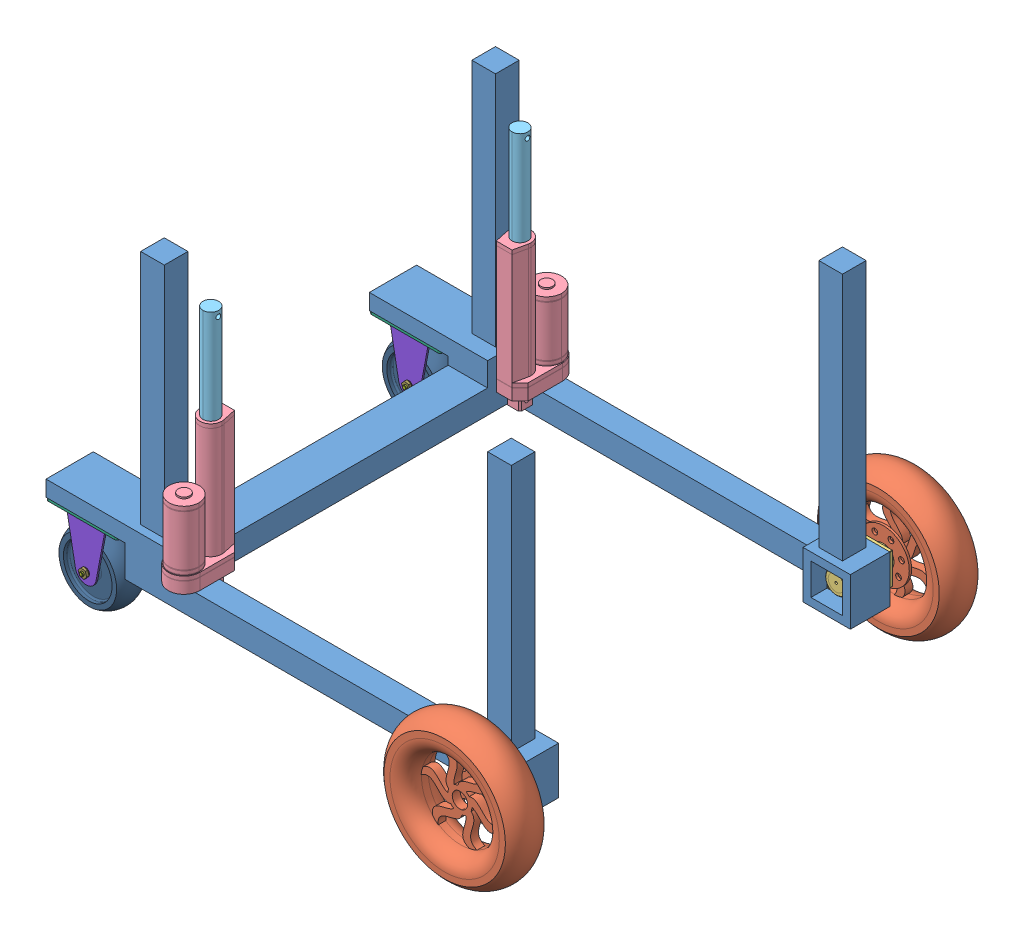
SolidWorks assembly Automatic Wheel Chair, configuration Default. Lengths in mm.
Overall size (717.52 470.88 599).
25 component instances, 12 part files, 35 mates.
Components (placement in the parent):
- Part1^Automatic Wheel Chair-1: Part1^Automatic Wheel Chair [Default] x (1 0 0) z (0 1 0) size (600 470 375) (virtual)
- motorbike wheel-1: motorbike wheel [Default] at (228.5832 -15.7536 275.1) x (0 0 1) z (0.96319 0.268823 0) size (48.77 178.47 178.47)
- motorbike wheel-2: motorbike wheel [Default] at (195.8761 -5.9162 -275.1) x (0 0 -1) z (-0.655088 0.755552 0) size (48.77 178.47 178.47)
- LINOS-FI-1030-35C_bulk-1: LINOS-FI-1030-35C_bulk [Default] at (220 15 227) x (0 0 1) z (-1 0 0) size (60.2 40 40)
- LINOS-FI-1030-35C_bulk-2: LINOS-FI-1030-35C_bulk [Default] at (220 15 -227) x (0 0 -1) z (1 0 0) size (60.2 40 40)
- 100mm Body.step-3: 100mm Body.step [Default] at (-180 30 -203) x (0 0 1) z (1 0 0) size (74 184 40)
- 100mm Rod.step-2: 100mm Rod.step [Default] at (-180 315.7736 -196) x (1 0 0) z (0 0 -1) size (20.01 121 20)
- 100mm Body.step-2: 100mm Body.step [Default] at (-180 30 203) x (0 0 -1) z (-1 0 0) size (74 184 40)
- 100mm Rod.step-1: 100mm Rod.step [Default] at (-180 315.7736 196) x (-1 0 0) z (0 0 1) size (20.01 121 20)
- Castor Wheel Assembly-3: Castor Wheel Assembly [Default] at (-334.542 8.6584 218.6333) x (0 0 -1) z (1 0 0) size (60 128.96 125.41)
  - Top-1: Top [Default] at (13.6333 28.3416 29.542) size (60 15.5 90)
  - Holder-1: Holder [Default] at (37.7896 -35.6584 26.7167) x (-0.998933 0 -0.046183) z (0.04107 -0.457338 -0.888344) size (50 12 12)
  - HOLDER 2-1: HOLDER 2 [Default] at (-5.2161 -32.9337 4.1925) x (-0.998933 0 -0.046183) z (0.046183 0 -0.998933) size (40 78 51.06)
  - bottom-1: bottom [Default] at (13.6333 18.3416 29.542) x (0.999827 0 0.018618) z (-0.018618 0 0.999827) size (27 8 25.19)
  - Wheel-1: Wheel [Default] at (0.3296 -35.6584 24.9849) x (0.998933 0 0.046183) z (0.035525 -0.638971 -0.76841) size (35 88 88)
  - washer-1: washer [Default] at (-6.6629 -35.6584 24.6616) x (0.998933 0 0.046183) z (-0.044089 0.297668 0.953651) size (0.5 10 10)
  - Nut-1: Nut [Default] at (-10.1592 -35.6584 24.4999) x (0.998933 0 0.046183) z (-0.03002 0.759916 0.649328) size (3 10 11.55)
- Castor Wheel Assembly-4: Castor Wheel Assembly [Default] at (-334.542 8.6584 -191.3667) x (0 0 -1) z (1 0 0) size (60 128.96 125.41)
  - Top-1: Top [Default] at (13.6333 28.3416 29.542) size (60 15.5 90)
  - Holder-1: Holder [Default] at (37.7896 -35.6584 26.7167) x (-0.998933 0 -0.046183) z (0.04107 -0.457338 -0.888344) size (50 12 12)
  - HOLDER 2-1: HOLDER 2 [Default] at (-5.2161 -32.9337 4.1925) x (-0.998933 0 -0.046183) z (0.046183 0 -0.998933) size (40 78 51.06)
  - bottom-1: bottom [Default] at (13.6333 18.3416 29.542) x (0.999827 0 0.018618) z (-0.018618 0 0.999827) size (27 8 25.19)
  - Wheel-1: Wheel [Default] at (0.3296 -35.6584 24.9849) x (0.998933 0 0.046183) z (0.035525 -0.638971 -0.76841) size (35 88 88)
  - washer-1: washer [Default] at (-6.6629 -35.6584 24.6616) x (0.998933 0 0.046183) z (-0.044089 0.297668 0.953651) size (0.5 10 10)
  - Nut-1: Nut [Default] at (-10.1592 -35.6584 24.4999) x (0.998933 0 0.046183) z (-0.03002 0.759916 0.649328) size (3 10 11.55)
Mates (geometry in assembly coordinates):
- InPlace1: in place: plane of Part1^Automatic Wheel Chair-1 through (0 0 0) normal (0 1 0); moOrthogonalPlaneRef_w of Part1^Automatic Wheel Chair-1 through (0 0 0) normal (0 0 -1); plane of Part1^Automatic Wheel Chair-1 through (0 0 0) normal (1 0 0); unknown of Part1^Automatic Wheel Chair-1
- Coincident1: coincident aligned: 
- Coincident2: coincident aligned: plane of Part1^Automatic Wheel Chair-1 through (0 0 0) normal (0 0 -1)
- Coincident3: coincident anti-aligned: plane of Part1^Automatic Wheel Chair-1 through (0 0 0) normal (1 0 0)
- Parallel3: parallel anti-aligned: plane of Part1^Automatic Wheel Chair-1 through (0 30 235) normal (0 0 1); plane of motorbike wheel-1 through (220 15 257.1) normal (0 0 -1)
- Parallel4: parallel anti-aligned: plane of Part1^Automatic Wheel Chair-1 through (0 30 -235) normal (0 0 -1); plane of motorbike wheel-2 through (220 15 -257.1) normal (0 0 1)
- Concentric19: concentric anti-aligned: cylinder of motorbike wheel-1 through (220 15 260.1) axis (0 0 1) radius 9.7956; cylinder of LINOS-FI-1030-35C_bulk-1 through (220 15 257) axis (0 0 -1) radius 14.25
- Concentric20: concentric anti-aligned: cylinder of motorbike wheel-2 through (220 15 -247.1) axis (0 0 -1) radius 9.7956; cylinder of LINOS-FI-1030-35C_bulk-2 through (220 15 -257) axis (0 0 1) radius 14.25
- Coincident36: coincident anti-aligned: plane of Part1^Automatic Wheel Chair-1 through (200 35 -235) normal (0 -1 0); plane of LINOS-FI-1030-35C_bulk-2 through (240 35 -249) normal (0 1 0)
- Coincident37: coincident anti-aligned: plane of Part1^Automatic Wheel Chair-1 through (200 35 -235) normal (0 -1 0); plane of LINOS-FI-1030-35C_bulk-1 through (200 35 249) normal (0 1 0)
- Coincident38: coincident anti-aligned: plane of Part1^Automatic Wheel Chair-1 through (200 -5 -235) normal (1 0 0); plane of LINOS-FI-1030-35C_bulk-1 through (200 15 227) normal (-1 0 0)
- Coincident39: coincident anti-aligned: plane of Part1^Automatic Wheel Chair-1 through (240 -5 -235) normal (-1 0 0); plane of LINOS-FI-1030-35C_bulk-2 through (240 15 -227) normal (1 0 0)
- Coincident40: coincident aligned: plane of Part1^Automatic Wheel Chair-1 through (0 30 -205) normal (0 0 1); plane of LINOS-FI-1030-35C_bulk-2 through (240 -5 -205) normal (0 0 1)
- Coincident41: coincident aligned: plane of Part1^Automatic Wheel Chair-1 through (0 30 205) normal (0 0 -1); plane of LINOS-FI-1030-35C_bulk-1 through (200 -5 205) normal (0 0 -1)
- Coincident42: coincident anti-aligned: plane of motorbike wheel-1 through (220 15 257.1) normal (0 0 -1); plane of LINOS-FI-1030-35C_bulk-1 through (220 15 257.1) normal (0 0 1)
- Coincident43: coincident anti-aligned: plane of motorbike wheel-2 through (220 15 -257.1) normal (0 0 1); plane of LINOS-FI-1030-35C_bulk-2 through (220 15 -257.1) normal (0 0 -1)
- Concentric21: concentric aligned: cylinder of 100mm Body.step-2 through (-180 21.7157 196) axis (0 1 0) radius 10; cylinder of 100mm Rod.step-1 through (-180 194.7736 196) axis (0 1 0) radius 10
- LimitDistance1: limit distance = 119.7736 mm aligned: plane of 100mm Rod.step-1 through (-180 315.7736 196) normal (0 1 0); plane of 100mm Body.step-2 through (-180 196 196) normal (0 1 0)
- Parallel1: parallel aligned: cylinder of 100mm Body.step-2 through (-162.5147 21 196) axis (-1 0 0) radius 3; cylinder of 100mm Rod.step-1 through (-169.999 308.7736 196) axis (-1 0 0) radius 3
- Coincident58: coincident anti-aligned: plane of Part1^Automatic Wheel Chair-1 through (0 30 0) normal (0 1 0); plane of 100mm Body.step-2 through (-180 30 230) normal (0 -1 0)
- Coincident59: coincident anti-aligned: plane of Part1^Automatic Wheel Chair-1 through (-200 30 0) normal (1 0 0); plane of 100mm Body.step-2 through (-200 50 230) normal (-1 0 0)
- Coincident60: coincident anti-aligned: plane of Part1^Automatic Wheel Chair-1 through (0 30 205) normal (0 0 -1); plane of 100mm Body.step-2 through (-173 12 205) normal (0 0 1)
- Concentric22: concentric aligned: cylinder of 100mm Body.step-3 through (-180 21.7157 -196) axis (0 1 0) radius 10; cylinder of 100mm Rod.step-2 through (-180 194.7736 -196) axis (0 1 0) radius 10
- LimitDistance2: limit distance = 119.7736 mm aligned: plane of 100mm Rod.step-2 through (-180 315.7736 -196) normal (0 1 0); plane of 100mm Body.step-3 through (-180 196 -196) normal (0 1 0)
- Parallel5: parallel aligned: cylinder of 100mm Body.step-3 through (-197.4853 21 -196) axis (1 0 0) radius 3; cylinder of 100mm Rod.step-2 through (-190.001 308.7736 -196) axis (1 0 0) radius 3
- Coincident61: coincident anti-aligned: plane of Part1^Automatic Wheel Chair-1 through (-200 30 0) normal (1 0 0); plane of 100mm Body.step-3 through (-200 50 -230) normal (-1 0 0)
- Coincident62: coincident anti-aligned: plane of Part1^Automatic Wheel Chair-1 through (0 30 0) normal (0 1 0); plane of 100mm Body.step-3 through (-180 30 -230) normal (0 -1 0)
- Coincident63: coincident anti-aligned: plane of Part1^Automatic Wheel Chair-1 through (0 30 -205) normal (0 0 1); plane of 100mm Body.step-3 through (-187 12 -205) normal (0 0 -1)
- Coincident65: coincident aligned: plane of 100mm Rod.step-2 through (-180 315.7736 -196) normal (0 1 0); plane of 100mm Rod.step-1 through (-180 315.7736 196) normal (0 1 0)
- Coincident66: coincident anti-aligned: plane of Part1^Automatic Wheel Chair-1 through (-350 40 -235) normal (0 -1 0); plane of Castor Wheel Assembly-4/Top-1 through (-305 40 -205) normal (0 1 0)
- Coincident67: coincident anti-aligned: plane of Part1^Automatic Wheel Chair-1 through (-350 40 175) normal (0 -1 0); plane of Castor Wheel Assembly-3/Top-1 through (-305 40 205) normal (0 1 0)
- Coincident68: coincident aligned: plane of Part1^Automatic Wheel Chair-1 through (0 30 235) normal (0 0 1); plane of Castor Wheel Assembly-3/Top-1 through (-350 40 235) normal (0 0 1)
- Coincident69: coincident aligned: plane of Part1^Automatic Wheel Chair-1 through (-350 0 0) normal (-1 0 0); plane of Castor Wheel Assembly-3/Top-1 through (-350 40 235) normal (-1 0 0)
- Coincident70: coincident aligned: plane of Part1^Automatic Wheel Chair-1 through (-250 60 -175) normal (0 0 1); plane of Castor Wheel Assembly-4/Top-1 through (-350 40 -175) normal (0 0 1)
- Coincident71: coincident aligned: plane of Part1^Automatic Wheel Chair-1 through (-350 0 0) normal (-1 0 0); plane of Castor Wheel Assembly-4/Top-1 through (-350 40 -175) normal (-1 0 0)
